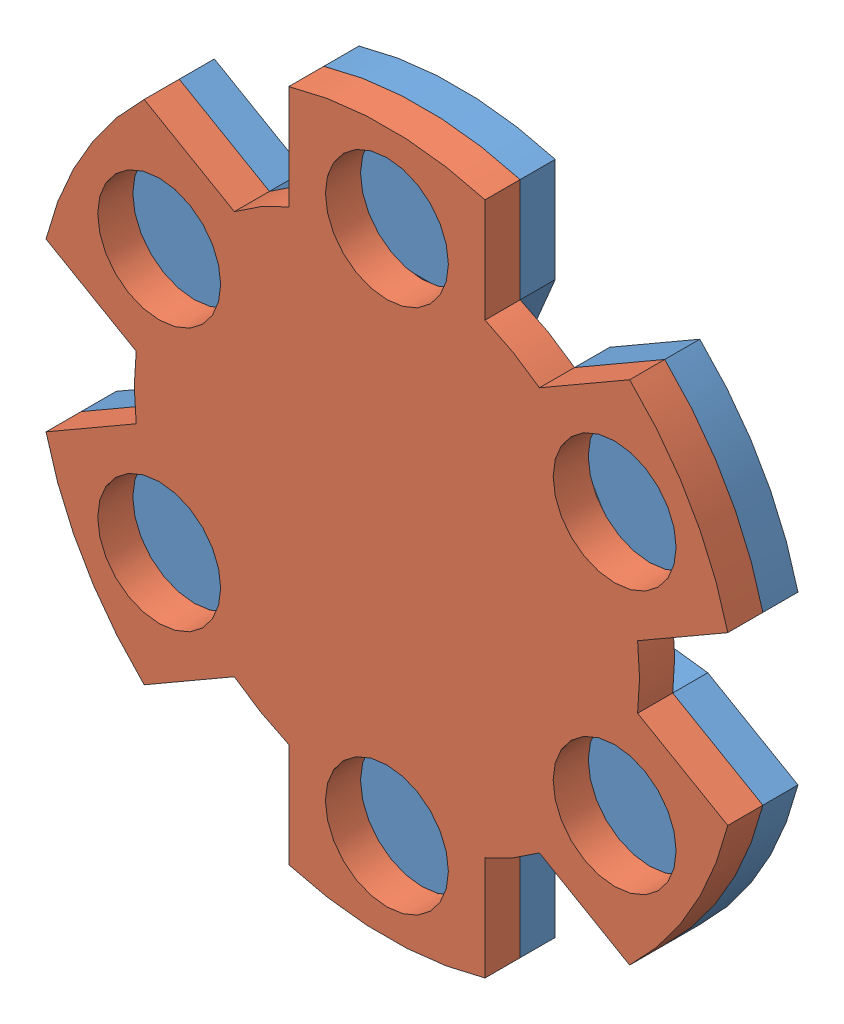
SolidWorks assembly magnetic_mount, configuration Default. Lengths in mm.
Overall size (61.68 63.5 6.35).
2 component instances, 2 part files, 0 mates.
Components (placement in the parent):
- magnetic_mount_front-1: magnetic_mount_front [Default] at (8.6967 17.7639 -18.2452) size (61.68 63.5 3.17)
- fiducial_mount_2-1: fiducial_mount_2 [Default] at (8.6967 17.7639 -15.0702) size (61.68 63.5 3.17)
